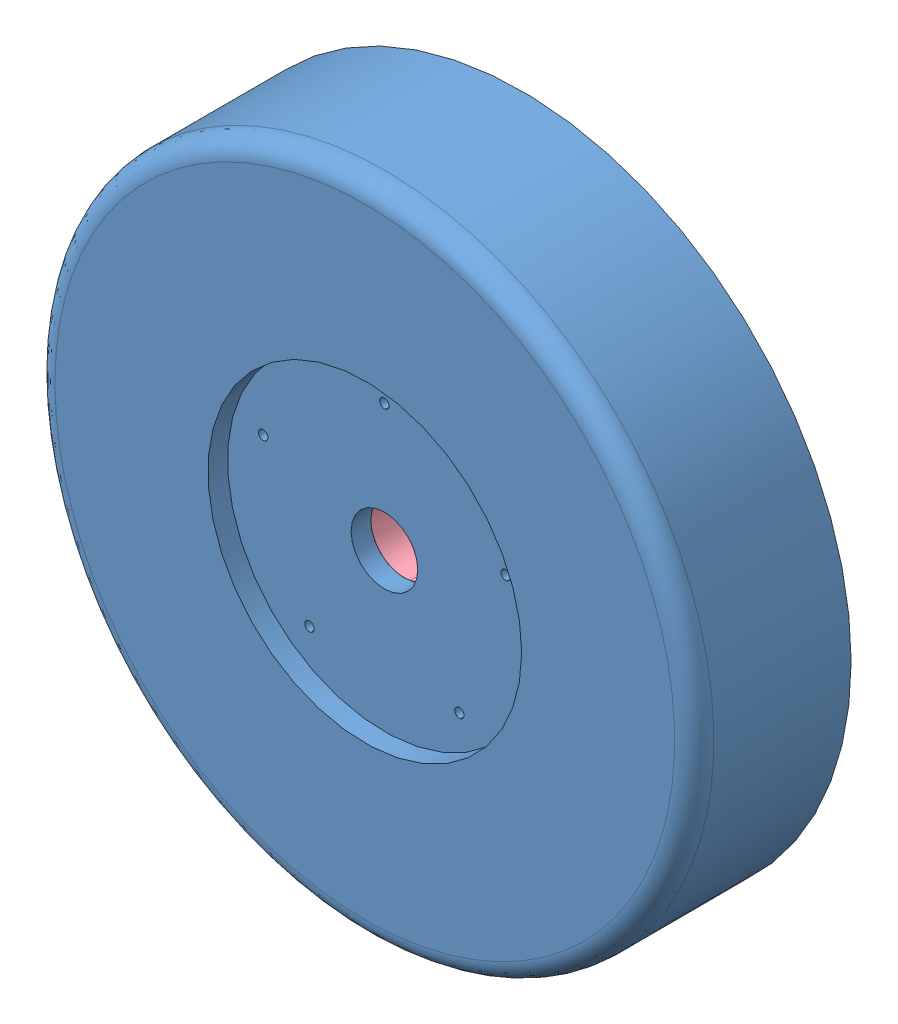
SolidWorks assembly Motor_assembly_rev1, configuration Default. Lengths in mm.
Overall size (168 168 40).
4 component instances, 4 part files, 7 mates.
Components (placement in the parent):
- Motor_cover_rev1-1: Motor_cover_rev1 [Default] at (-15.6766 35.7639 69.6895) x (0 0 -1) z (1 0 0) size (40 168 168)
- Motor_stator-1: Motor_stator [Default] at (-15.6766 90.7639 49.6895) x (0 0 1) z (-1 0 0) size (20 160 160)
- Motor_circuit_board-1: Motor_circuit_board [Default] at (-15.6766 35.7639 41.6895) size (80 120 8)
- Motor_Rotor_rev1-2: Motor_Rotor_rev1 [Default] at (-15.6766 35.7639 49.6895) x (0.939385 -0.342865 0) z (0 0 1) size (108 108 20)
Mates (geometry in assembly coordinates):
- Concentric2: concentric anti-aligned: cylinder of Motor_cover_rev1-1 through (-15.6766 35.7639 39.6895) axis (0 0 1) radius 11; cylinder of Motor_stator-1 through (-15.6766 35.7639 -37.4509) axis (0 0 -1) radius 55
- Coincident2: coincident anti-aligned: plane of Motor_cover_rev1-1 through (-15.6766 35.7639 69.6895) normal (0 0 -1); plane of Motor_stator-1 through (-15.6766 90.7639 69.6895) normal (0 0 1)
- Coincident3: coincident anti-aligned: plane of Motor_stator-1 through (-15.6766 90.7639 49.6895) normal (0 0 -1); plane of Motor_circuit_board-1 through (-15.6766 35.7639 49.6895) normal (0 0 1)
- Concentric3: concentric anti-aligned: cylinder of Motor_cover_rev1-1 through (-15.6766 35.7639 39.6895) axis (0 0 1) radius 11; cylinder of Motor_circuit_board-1 through (-15.6766 35.7639 49.6895) axis (0 0 -1) radius 60
- Concentric4: concentric aligned: cylinder of Motor_stator-1 through (-15.6766 35.7639 -37.4509) axis (0 0 -1) radius 55; cylinder of Motor_Rotor_rev1-2 through (-15.6766 35.7639 69.6895) axis (0 0 -1) radius 54
- Concentric5: concentric aligned: cylinder of Motor_cover_rev1-1 through (-15.6766 35.7639 39.6895) axis (0 0 1) radius 11; cylinder of Motor_Rotor_rev1-2 through (-15.6766 35.7639 49.6885) axis (0 0 1) radius 13
- Coincident4: coincident aligned: plane of Motor_stator-1 through (-15.6766 90.7639 49.6895) normal (0 0 -1); plane of Motor_Rotor_rev1-2 through (-15.6766 35.7639 49.6895) normal (0 0 -1)
